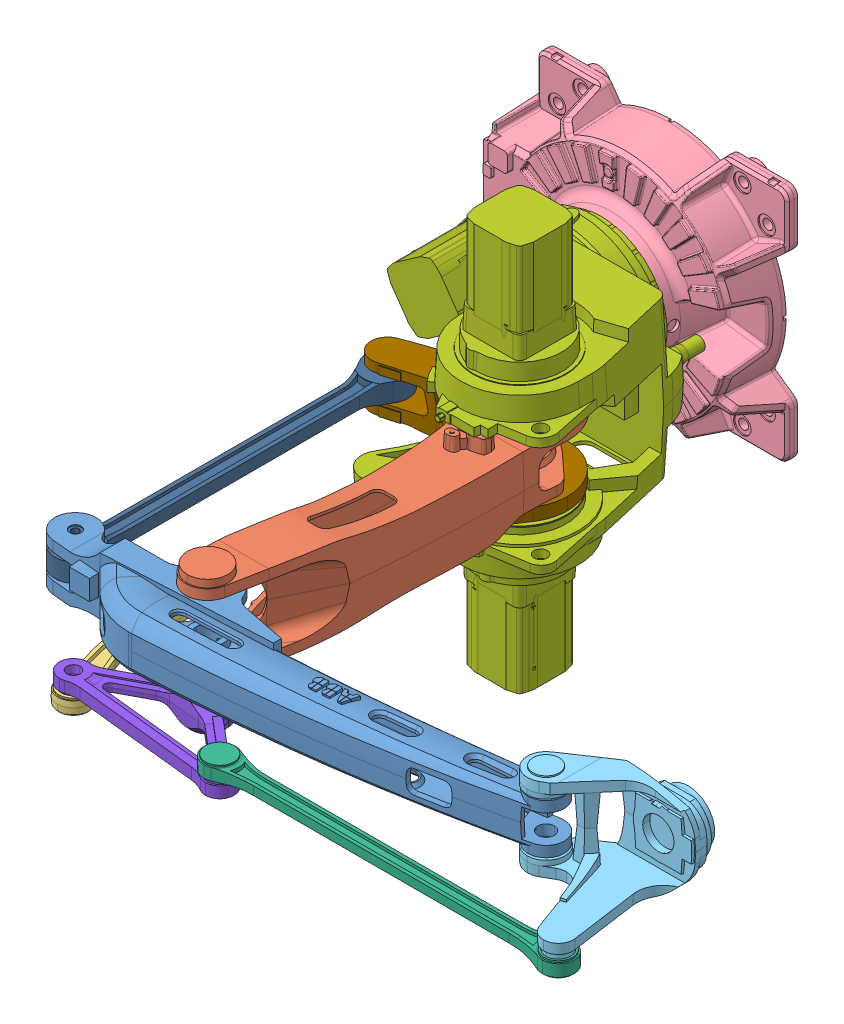
SolidWorks assembly IRB-460-SW, configuration 默认. Lengths in mm.
Overall size (2218.73 1174.02 1974.28).
11 component instances, 10 part files, 0 mates.
Components (placement in the parent):
- IRB-460^IRB-460-SW-1: IRB-460^IRB-460-SW [默认] at origin size (2006.55 1174.02 1974.28) (virtual)
  - Upper arm^IRB-460_IRB-460-SW-1: Upper arm^IRB-460_IRB-460-SW [默认] at origin size (1542.5 204.74 287.36) (virtual)
  - Lower arm^IRB-460_IRB-460-SW-1: Lower arm^IRB-460_IRB-460-SW [默认] at origin size (314.03 294 1159) (virtual)
  - lower link^IRB-460_IRB-460-SW-1: lower link^IRB-460_IRB-460-SW [默认] at origin size (171.35 51.83 1041) (virtual)
  - Foot^IRB-460_IRB-460-SW-1: Foot^IRB-460_IRB-460-SW [默认] at (-51.2795 15.6414 -31.2679) size (776.57 720.03 285.22) (virtual)
  - Tilt^IRB-460_IRB-460-SW-1: Tilt^IRB-460_IRB-460-SW [默认] at origin size (382.5 312 455.34) (virtual)
  - upper link^IRB-460_IRB-460-SW-1: upper link^IRB-460_IRB-460-SW [默认] at origin size (1121 45 187.44) (virtual)
  - swing^IRB-460_IRB-460-SW-1: swing^IRB-460_IRB-460-SW [默认] at origin size (752.53 1174.02 752) (virtual)
  - link plate^IRB-460_IRB-460-SW-1: link plate^IRB-460_IRB-460-SW [默认] at origin size (581.95 139 326.83) (virtual)
  - P arm^IRB-460_IRB-460-SW-1: P arm^IRB-460_IRB-460-SW [默认] at origin size (595 187 361.79) (virtual)
  - P link^IRB-460_IRB-460-SW-1: P link^IRB-460_IRB-460-SW [默认] at origin size (135.71 135 1070) (virtual)
